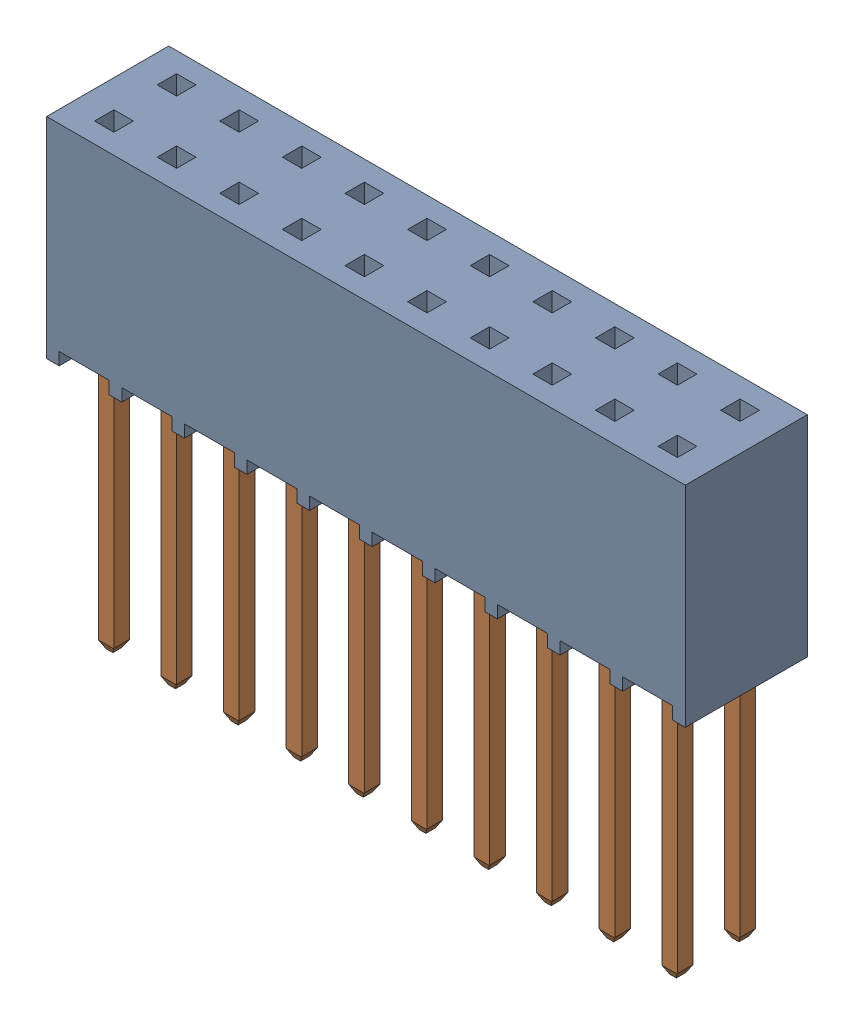
SolidWorks assembly SSQ-110-03-T-D, configuration Default. Lengths in mm.
Overall size (25.91 18.52 4.95).
2 component instances, 2 part files, 0 mates.
Components (placement in the parent):
- SSQ-110-03-T-D_2-1: SSQ-110-03-T-D_2 [Default] at origin size (25.91 8.51 4.95)
- SSQ-110-03-T-D_1-1: SSQ-110-03-T-D_1 [Default] at (0 -10.0076 0) size (23.9 11.02 3.76)
